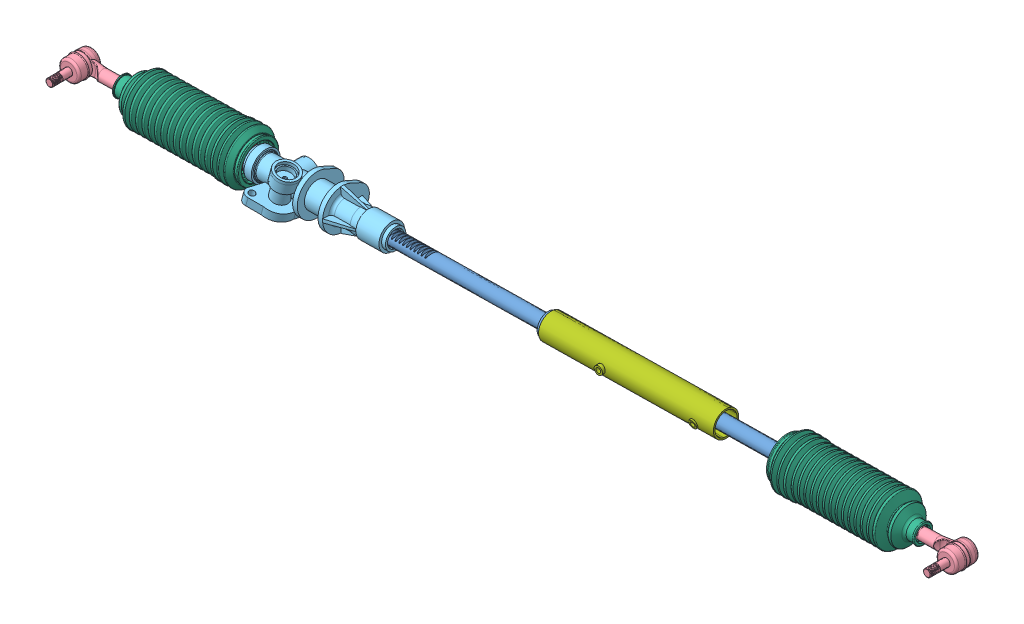
SolidWorks assembly Tie_rod_completed_lastly, configuration Default. Lengths in mm.
Overall size (1518.73 95.85 113.62).
11 component instances, 7 part files, 21 mates.
Components (placement in the parent):
- THANH RĂNG-1: THANH RĂNG [Default] x (-0.009959 0.120472 -0.992667) z (0.999937 0.006397 -0.009256) size (38 38 898)
- KHỚP CẦU 3-1: KHỚP CẦU 3 [Default] at (1.9999 0.0128 -0.0185) x (0.999937 0.006397 -0.009256) z (-0.005235 0.992696 0.120528) size (48.52 36 36)
- ROTUYN TRONG-1: ROTUYN TRONG [Default] at (1.8464 0.0118 -0.0171) x (-0.999937 -0.006397 0.009256) z (0.010223 -0.172949 0.984878) size (257.66 24 24)
- ROTUYN NGOÀI-1: ROTUYN NGOÀI [Default] at (-290.0734 -1.8694 9.3425) x (0.999937 0.006397 -0.009256) z (0.006378 -0.999978 -0.002069) size (90.98 73 54.28)
- KHỚP CẦU 3-2: KHỚP CẦU 3 [Default] at (897.9432 5.7441 -8.312) x (-0.999937 -0.006397 0.009256) z (-0.005216 0.992467 0.122404) size (48.52 36 36)
- ROTUYN TRONG-2: ROTUYN TRONG [Default] at (898.0966 5.7451 -8.3134) x (0.999937 0.006397 -0.009256) z (-0.005216 0.992475 0.122335) size (257.66 24 24)
- ROTUYN NGOÀI-2: ROTUYN NGOÀI [Default] at (1190.1391 7.7193 -4.3602) x (-0.999937 -0.006397 0.009256) z (-0.006543 0.999852 -0.015916) size (90.98 73 54.28)
- VỎ CƠ CẤU LÁI-1: VỎ CƠ CẤU LÁI [Default] at (238.2713 1.5242 -2.2056) x (-0.999937 -0.006397 0.009256) z (0.009256 0.00003 0.999957) size (236.3 72.67 100.51)
- CAO SU CHẤN BỤI-1: CAO SU CHẤN BỤI [Default] at (6.9996 0.0448 -0.0648) x (-0.999937 -0.006397 0.009256) z (0.009256 0.00003 0.999957) size (230.52 87.2 87.2)
- CAO SU CHẤN BỤI-2: CAO SU CHẤN BỤI [Default] at (897.9432 5.7441 -8.312) x (0.999937 0.006397 -0.009256) z (0.009256 0.00003 0.999957) size (230.52 87.2 87.2)
- THƯỚC LÁI-1: THƯỚC LÁI [Default] at (500.6483 3.2026 -4.6343) x (0.999937 0.006397 -0.009256) z (0.005848 -0.998295 -0.058079) size (295 48.35 43.5)
Mates (geometry in assembly coordinates):
- Coincident2: coincident: point of THANH RĂNG-1
- Concentric1: concentric aligned: cylinder of THANH RĂNG-1 through (597.9621 3.8252 -5.5351) axis (-0.999937 -0.006397 0.009256) radius 11.5; cylinder of KHỚP CẦU 3-1 through (1.8464 0.0118 -0.0171) axis (-0.999937 -0.006397 0.009256) radius 18
- Coincident3: coincident anti-aligned: plane of THANH RĂNG-1 through (24.9984 0.1599 -0.2314) normal (-0.999937 -0.006397 0.009256); plane of KHỚP CẦU 3-1 through (24.9984 0.1599 -0.2314) normal (0.999937 0.006397 -0.009256)
- Concentric2: concentric anti-aligned: cylinder of THANH RĂNG-1 through (597.9621 3.8252 -5.5351) axis (-0.999937 -0.006397 0.009256) radius 11.5; cylinder of ROTUYN TRONG-1 through (-9.1529 -0.0586 0.0847) axis (0.999937 0.006397 -0.009256) radius 6.5
- Coincident5: coincident anti-aligned: plane of KHỚP CẦU 3-1 through (1.829 0.2226 -1.7543) normal (-0.999937 -0.006397 0.009256); plane of ROTUYN TRONG-1 through (1.8464 0.0118 -0.0171) normal (0.999937 0.006397 -0.009256)
- Concentric3: concentric aligned: cylinder of ROTUYN TRONG-1 through (-9.1529 -0.0586 0.0847) axis (0.999937 0.006397 -0.009256) radius 6.5; cylinder of ROTUYN NGOÀI-1 through (-254.8874 -1.6305 2.3594) axis (0.999937 0.006397 -0.009256) radius 9.5
- Coincident6: coincident anti-aligned: plane of ROTUYN TRONG-1 through (-255.1373 -1.6321 2.3617) normal (-0.999937 -0.006397 0.009256); plane of ROTUYN NGOÀI-1 through (-255.1524 -6.8333 -2.8606) normal (0.999937 0.006397 -0.009256)
- Concentric4: concentric anti-aligned: cylinder of THANH RĂNG-1 through (597.9621 3.8252 -5.5351) axis (-0.999937 -0.006397 0.009256) radius 11.5; cylinder of KHỚP CẦU 3-2 through (898.0966 5.7451 -8.3134) axis (0.999937 0.006397 -0.009256) radius 18
- Coincident7: coincident anti-aligned: plane of THANH RĂNG-1 through (897.9432 5.7441 -8.312) normal (0.999937 0.006397 -0.009256); plane of KHỚP CẦU 3-2 through (898.1226 3.5419 9.5519) normal (-0.999937 -0.006397 0.009256)
- Concentric5: concentric aligned: cylinder of THANH RĂNG-1 through (597.9621 3.8252 -5.5351) axis (-0.999937 -0.006397 0.009256) radius 11.5; cylinder of ROTUYN TRONG-2 through (909.0959 5.8155 -8.4152) axis (-0.999937 -0.006397 0.009256) radius 6.5
- Coincident8: coincident anti-aligned: circle of KHỚP CẦU 3-2; plane of ROTUYN TRONG-2 through (898.0966 5.7451 -8.3134) normal (-0.999937 -0.006397 0.009256)
- Concentric6: concentric aligned: cylinder of ROTUYN TRONG-2 through (909.0959 5.8155 -8.4152) axis (-0.999937 -0.006397 0.009256) radius 6.5; cylinder of ROTUYN NGOÀI-2 through (1154.8304 7.3874 -10.6899) axis (-0.999937 -0.006397 0.009256) radius 9.5
- Coincident9: coincident anti-aligned: plane of ROTUYN TRONG-2 through (1155.0804 7.389 -10.6922) normal (0.999937 0.006397 -0.009256); plane of ROTUYN NGOÀI-2 through (1154.9986 12.5168 -15.9861) normal (-0.999937 -0.006397 0.009256)
- Concentric7: concentric anti-aligned: cylinder of THANH RĂNG-1 through (597.9621 3.8252 -5.5351) axis (-0.999937 -0.006397 0.009256) radius 11.5; cylinder of VỎ CƠ CẤU LÁI-1 through (238.2713 1.5242 -2.2056) axis (0.999937 0.006397 -0.009256) radius 21.75
- Coincident10: coincident anti-aligned: plane of KHỚP CẦU 3-1 through (1.8206 2.1813 -17.8865) normal (0.999937 0.006397 -0.009256); plane of VỎ CƠ CẤU LÁI-1 through (1.9999 0.0128 -0.0185) normal (-0.999937 -0.006397 0.009256)
- Concentric8: concentric aligned: cylinder of ROTUYN TRONG-1 through (-9.1529 -0.0586 0.0847) axis (0.999937 0.006397 -0.009256) radius 6.5; cylinder of CAO SU CHẤN BỤI-1 through (6.9996 0.0448 -0.0648) axis (0.999937 0.006397 -0.009256) radius 15.4083
- Coincident11: coincident anti-aligned: plane of VỎ CƠ CẤU LÁI-1 through (7.12 -18.7896 -0.0654) normal (-0.999937 -0.006397 0.009256); plane of CAO SU CHẤN BỤI-1 through (7.2184 -34.1645 -0.0658) normal (0.999937 0.006397 -0.009256)
- Concentric9: concentric: cylinder of ROTUYN NGOÀI-2 through (1154.8304 7.3874 -10.6899) axis (-0.999937 -0.006397 0.009256) radius 9.5; cylinder of CAO SU CHẤN BỤI-2 through (897.9432 5.7441 -8.312) axis (-0.999937 -0.006397 0.009256) radius 15.4083
- Coincident12: coincident aligned: plane of KHỚP CẦU 3-2 through (898.1226 3.5419 9.5519) normal (-0.999937 -0.006397 0.009256); plane of CAO SU CHẤN BỤI-2 through (897.7243 39.9534 -8.311) normal (-0.999937 -0.006397 0.009256)
- Concentric10: concentric: cylinder of THANH RĂNG-1 through (597.9621 3.8252 -5.5351) axis (-0.999937 -0.006397 0.009256) radius 11.5; cylinder of THƯỚC LÁI-1 through (795.6296 5.0896 -7.3649) axis (-0.999937 -0.006397 0.009256) radius 21.75
- Coincident13: coincident anti-aligned: plane of THANH RĂNG-1 through (500.6483 3.2026 -4.6343) normal (0.999937 0.006397 -0.009256); plane of THƯỚC LÁI-1 through (500.6483 3.2026 -4.6343) normal (-0.999937 -0.006397 0.009256)
